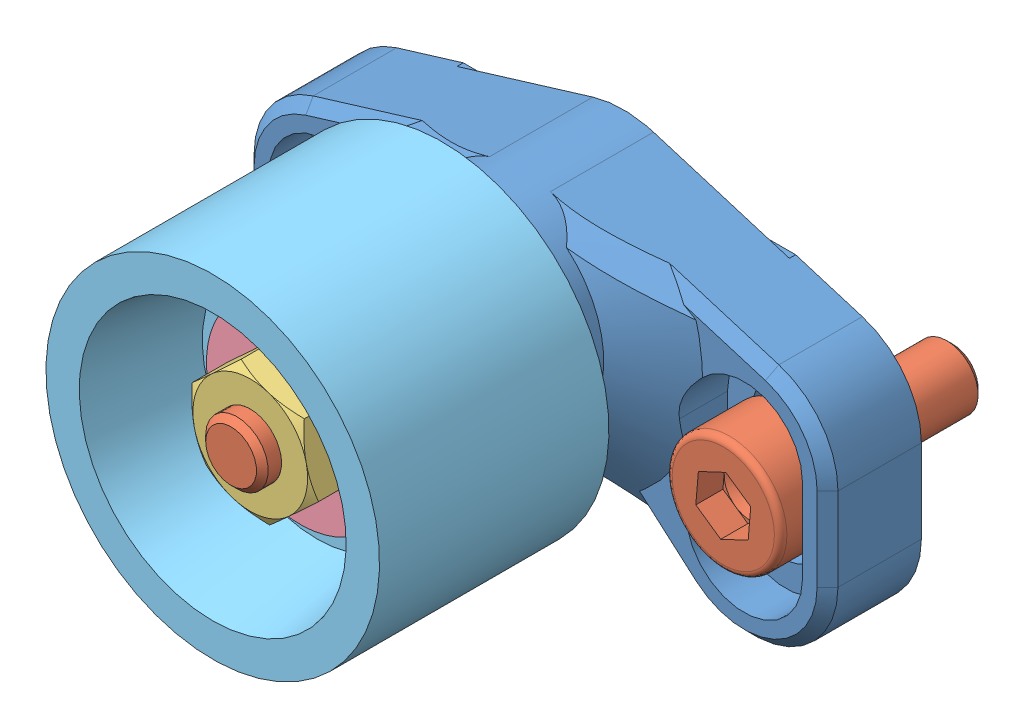
SolidWorks assembly bg_Kettenspanner, configuration Standard. Lengths in mm.
Overall size (28 18.28 25.48).
10 component instances, 6 part files, 17 mates.
Components (placement in the parent):
- pipemouse_KettenspannerBlock-1: pipemouse_KettenspannerBlock [Standard] at (-4.7133 -1.8447 28) size (28 16.13 7)
- socket head cap screw_din-1: socket head cap screw_din [DIN 912 M3 x 16 --- 16N] at (-4.7133 2.1553 28.1) x (0 0 1) z (-1 0 0) size (19 5.5 5.5)
- hex nut style 1 gradeab_din-1: hex nut style 1 gradeab_din [Hexagon Nut ISO 4032 - M3 - W - N] at (-4.7133 2.1553 34.9) x (0.999968 0.007955 0) z (0 0 1) size (5.5 6.35 2.4)
- plain washer large_din-1: plain washer large_din [Washer DIN 9021 - 3.2] at (-4.7133 2.1553 35) x (0 0 -1) z (1 0 0) size (0.8 9 9)
- socket head cap screw_din-2: socket head cap screw_din [DIN 912 M3 x 8 --- 8N] at (-14.7133 -1.6019 33.5) x (0 0 -1) z (0.996445 -0.084244 0) size (11 5.5 5.5)
- socket head cap screw_din-3: socket head cap screw_din [DIN 912 M3 x 8 --- 8N] at (5.2867 -1.7093 33.5) x (0 0 -1) z (0.996445 -0.084244 0) size (11 5.5 5.5)
- pipemouse_KettenspannRad-1: pipemouse_KettenspannRad [Standard] at (-4.7133 2.1553 31.9828) x (0 0 1) z (-0.999376 0.035307 0) size (12 16 16)
- pipemouse_Kugellager_8x3x4-1: pipemouse_Kugellager_8x3x4 [Standard] at (-4.7133 2.1553 39.9828) x (-1 0 0) z (0 0 -1) size (8 8 4)
- plain washer large_din-2: plain washer large_din [Washer DIN 9021 - 3.2] at (-4.7133 2.1553 42.9828) x (0 0 -1) z (0.891573 -0.452878 0) size (0.8 9 9)
- hex nut style 1 gradeab_din-2: hex nut style 1 gradeab_din [Hexagon Nut ISO 4032 - M3 - W - N] at (-4.7133 2.1553 46.1828) x (0.97662 0.214974 0) z (0 0 1) size (5.5 6.35 2.4)
Mates (geometry in assembly coordinates):
- Konzentrisch1: concentric aligned: cylinder of pipemouse_KettenspannerBlock-1 through (-4.7133 2.1553 31.1) axis (0 0 -1) radius 3; cylinder of socket head cap screw_din-1 through (-4.7133 2.1553 -3.65) axis (0 0 -1) radius 2.75
- Deckungsgleich1: coincident anti-aligned: plane of pipemouse_KettenspannerBlock-1 through (-4.7133 2.1553 31.1) normal (0 0 -1); plane of socket head cap screw_din-1 through (-4.7133 4.9053 31.1) normal (0 0 1)
- Konzentrisch3: concentric anti-aligned: cylinder of socket head cap screw_din-1 through (-4.7133 2.1553 -3.65) axis (0 0 -1) radius 1.5; cylinder of hex nut style 1 gradeab_din-1 through (-4.7133 2.1553 32.5) axis (0 0 1) radius 1.25
- Deckungsgleich3: coincident anti-aligned: plane of pipemouse_KettenspannerBlock-1 through (-4.7133 -1.8447 32.5) normal (0 0 1); plane of hex nut style 1 gradeab_din-1 through (-4.7386 5.3306 32.5) normal (0 0 -1)
- Konzentrisch4: concentric anti-aligned: cylinder of socket head cap screw_din-1 through (-4.7133 2.1553 -3.65) axis (0 0 -1) radius 1.5; cylinder of plain washer large_din-1 through (-4.7133 2.1553 69.925) axis (0 0 1) radius 1.6
- Deckungsgleich4: coincident anti-aligned: plane of pipemouse_KettenspannerBlock-1 through (-4.7133 2.1553 35) normal (0 0 1); plane of plain washer large_din-1 through (-4.7133 3.7553 35) normal (0 0 -1)
- Langloch1: slot anti-aligned: cylinder of socket head cap screw_din-2 through (-14.7133 -1.6019 65.25) axis (0 0 1) radius 1.5; plane of pipemouse_KettenspannerBlock-1 through (-16.3133 0.1553 32.5) normal (1 0 0); cylinder of pipemouse_KettenspannerBlock-1 through (-14.7133 0.1553 32.5) axis (0 0 -1) radius 1.6
- Deckungsgleich5: coincident anti-aligned: plane of pipemouse_KettenspannerBlock-1 through (-14.7133 0.1553 30.5) normal (0 0 1); plane of socket head cap screw_din-2 through (-14.4816 1.1383 30.5) normal (0 0 -1)
- Langloch2: slot anti-aligned: cylinder of socket head cap screw_din-3 through (5.2867 -1.7093 65.25) axis (0 0 1) radius 1.5; cylinder of pipemouse_KettenspannerBlock-1 through (5.2867 -3.8447 32.5) axis (0 0 -1) radius 1.6; cylinder of pipemouse_KettenspannerBlock-1 through (5.2867 0.1553 32.5) axis (0 0 -1) radius 1.6
- Deckungsgleich6: coincident anti-aligned: plane of pipemouse_KettenspannerBlock-1 through (5.2867 0.1553 30.5) normal (0 0 1); plane of socket head cap screw_din-3 through (5.5184 1.0309 30.5) normal (0 0 -1)
- Konzentrisch5: concentric anti-aligned: cylinder of pipemouse_KettenspannRad-1 through (-4.7133 2.1553 31.9828) axis (0 0 -1) radius 4; cylinder of pipemouse_Kugellager_8x3x4-1 through (-4.7133 2.1553 35.9828) axis (0 0 1) radius 4
- Deckungsgleich7: coincident anti-aligned: plane of pipemouse_KettenspannRad-1 through (-4.6586 3.7043 39.9828) normal (0 0 -1); plane of pipemouse_Kugellager_8x3x4-1 through (-4.7133 2.1553 39.9828) normal (0 0 1)
- Konzentrisch6: concentric anti-aligned: cylinder of socket head cap screw_din-1 through (-4.7133 2.1553 -3.65) axis (0 0 -1) radius 1.5; cylinder of pipemouse_Kugellager_8x3x4-1 through (-4.7133 2.1553 35.9828) axis (0 0 1) radius 1.5
- Konzentrisch7: concentric anti-aligned: cylinder of socket head cap screw_din-1 through (-4.7133 2.1553 -3.65) axis (0 0 -1) radius 1.5; cylinder of plain washer large_din-2 through (-4.7133 2.1553 77.9078) axis (0 0 1) radius 1.6
- Deckungsgleich8: coincident anti-aligned: plane of pipemouse_KettenspannRad-1 through (-4.5191 7.6519 42.9828) normal (0 0 1); plane of plain washer large_din-2 through (-3.9887 3.5818 42.9828) normal (0 0 -1)
- Konzentrisch8: concentric anti-aligned: cylinder of socket head cap screw_din-1 through (-4.7133 2.1553 -3.65) axis (0 0 -1) radius 1.5; cylinder of hex nut style 1 gradeab_din-2 through (-4.7133 2.1553 43.7828) axis (0 0 1) radius 1.25
- Deckungsgleich9: coincident anti-aligned: plane of plain washer large_din-2 through (-2.6753 6.1674 43.7828) normal (0 0 1); plane of hex nut style 1 gradeab_din-2 through (-5.3959 5.2565 43.7828) normal (0 0 -1)
